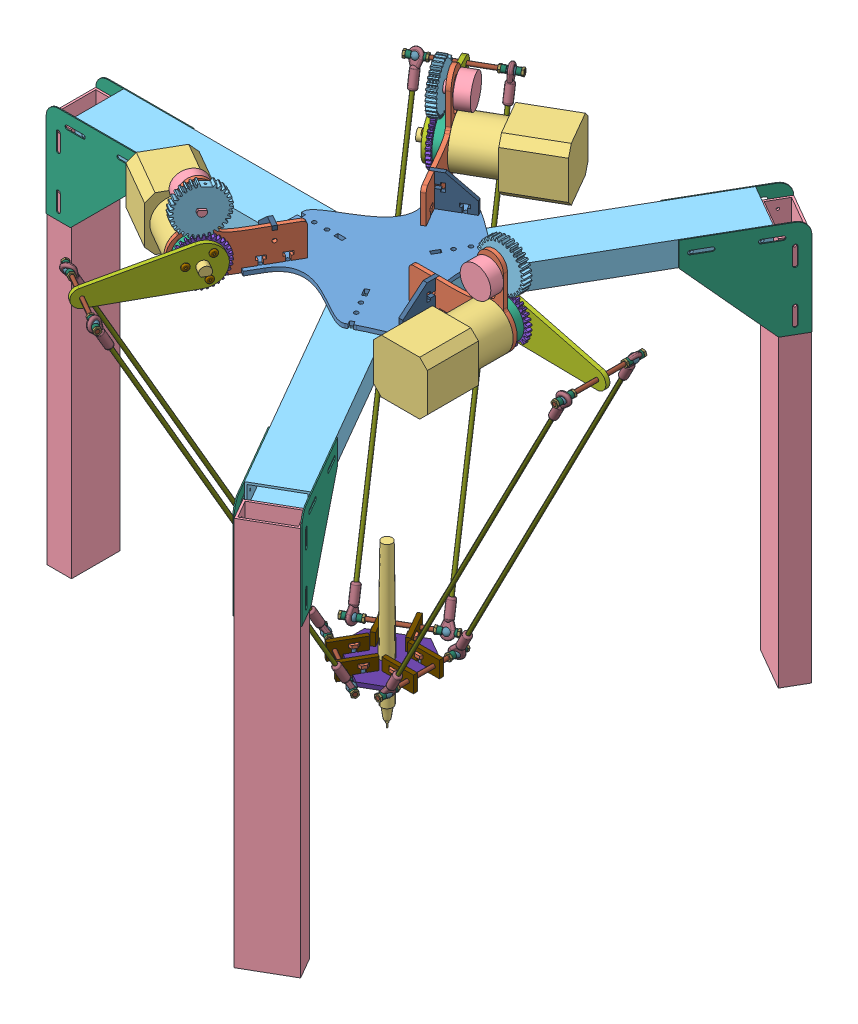
SolidWorks assembly robot, configuration Default. Lengths in mm.
Overall size (423 403.55 480.6).
179 component instances, 24 part files, 17 mates.
Components (placement in the parent):
- robot_base-2: robot_base [Default] at (60.4446 67.0831 10.1003) size (316.06 87.11 312.23)
  - baseplate-1: baseplate [Default] at (-6.2424 -10.4202 4.8167) size (143.92 3.17 142.53)
  - motor_plate-1: motor_plate [Default] at (95.6116 7.5795 20.7552) x (-1 0 0) z (0 0 -1) size (81.5 68.48 3.17)
  - stepper-1: stepper [Default] at (95.6116 7.5795 90.9552) x (0 0 -1) z (-1 0 0) size (92.2 42 42)
  - potentiometer2-1: potentiometer2 [Default] at (95.6111 42.9686 32.2552) x (0 0 -1) z (-0.02281 0.99974 0) size (26.5 24 24)
  - gear_pot-1: gear_pot [Default] at (95.6111 42.9686 6.4052) x (-0.303545 0.952817 0) z (0 0 1) size (37.03 37 6.35)
  - arm_upper_complete-1: arm_upper_complete [Default] at (88.6637 -5.6723 10.8016) x (0.795225 0.606314 0) z (0.606314 -0.795225 0) size (88.08 14.2 88.05) (flexible)
    - arm_collar-1: arm_collar [Default] at (13.5599 -1.2214 -6.3255) size (30.48 6.35 30.25)
    - arm_upper-1: arm_upper [Default] at (13.5599 -7.5714 -6.3255) x (-0.707107 0 -0.707107) z (0 1 0) size (92.08 30.48 3.17)
    - gear_stepper-1: gear_stepper [Default] at (13.5599 -4.3964 -6.3255) x (-0.959493 0 0.281733) z (0 1 0) size (37.03 37 3.17)
    - 4-40_12_screw-1: 4-40_12_screw [Default] at (4.761 5.1286 -1.2455) x (0.825951 0 0.563741) z (0.563741 0 -0.825951) size (5.41 14.2 5.41)
    - 4-40_12_screw-2: 4-40_12_screw [Default] at (22.3587 5.1286 -1.2455) x (0.604288 0 0.796766) z (0.796766 0 -0.604288) size (5.41 14.2 5.41)
    - 4-40_12_screw-3: 4-40_12_screw [Default] at (13.5599 5.1286 -16.4855) x (-0.60826 0 0.793738) z (0.793738 0 0.60826) size (5.41 14.2 5.41)
  - motor_plate_support-1: motor_plate_support [Default] at (49.4471 6.4708 20.7552) x (0 0 -1) z (1 0 0) size (28.57 28.57 3.17)
  - arm_upper_complete-4: arm_upper_complete [Default] at (-48.1298 -6.4819 -82.7041) x (-0.353553 0.707107 -0.612372) z (-0.353553 -0.707107 -0.612372) size (88.08 14.2 88.05) (flexible)
    - arm_collar-1: arm_collar [Default] at (13.5599 -1.2214 -6.3255) size (30.48 6.35 30.25)
    - arm_upper-1: arm_upper [Default] at (13.5599 -7.5714 -6.3255) x (-0.707107 0 -0.707107) z (0 1 0) size (92.08 30.48 3.17)
    - gear_stepper-1: gear_stepper [Default] at (13.5599 -4.3964 -6.3255) x (-0.959493 0 0.281733) z (0 1 0) size (37.03 37 3.17)
    - 4-40_12_screw-1: 4-40_12_screw [Default] at (4.761 5.1286 -1.2455) x (0.952213 0 0.305436) z (0.305436 0 -0.952213) size (5.41 14.2 5.41)
    - 4-40_12_screw-2: 4-40_12_screw [Default] at (22.3587 5.1286 -1.2455) x (0.806013 0 0.591898) z (0.591898 0 -0.806013) size (5.41 14.2 5.41)
    - 4-40_12_screw-3: 4-40_12_screw [Default] at (13.5599 5.1286 -16.4855) x (-0.35728 0 0.933997) z (0.933997 0 0.35728) size (5.41 14.2 5.41)
  - arm_upper_complete-5: arm_upper_complete [Default] at (-60.2082 -5.7041 83.3183) x (-0.396211 0.609973 0.686257) z (-0.304987 -0.792422 0.528252) size (88.08 14.2 88.05) (flexible)
    - arm_collar-1: arm_collar [Default] at (13.5599 -1.2214 -6.3255) size (30.48 6.35 30.25)
    - arm_upper-1: arm_upper [Default] at (13.5599 -7.5714 -6.3255) x (-0.707107 0 -0.707107) z (0 1 0) size (92.08 30.48 3.17)
    - gear_stepper-1: gear_stepper [Default] at (13.5599 -4.3964 -6.3255) x (-0.959493 0 0.281733) z (0 1 0) size (37.03 37 3.17)
    - 4-40_12_screw-1: 4-40_12_screw [Default] at (4.761 5.1286 -1.2455) x (0.645771 0 0.763531) z (0.763531 0 -0.645771) size (5.41 14.2 5.41)
    - 4-40_12_screw-2: 4-40_12_screw [Default] at (22.3587 5.1286 -1.2455) x (0.370008 0 0.929029) z (0.929029 0 -0.370008) size (5.41 14.2 5.41)
    - 4-40_12_screw-3: 4-40_12_screw [Default] at (13.5599 5.1286 -16.4855) x (-0.797851 0 0.602855) z (0.602855 0 0.797851) size (5.41 14.2 5.41)
  - stepper-4: stepper [Default] at (-131.7676 7.5795 49.9556) x (0.866025 0 0.5) z (0.5 0 -0.866025) size (92.2 42 42)
  - stepper-5: stepper [Default] at (17.4285 7.5792 -126.461) x (-0.866025 0 0.5) z (0.5 0 0.866025) size (92.2 42 42)
  - motor_plate-4: motor_plate [Default] at (-70.9726 7.5795 85.0556) x (0.5 0 -0.866025) z (0.866025 0 0.5) size (81.5 68.48 3.17)
  - motor_plate-5: motor_plate [Default] at (-43.3663 7.5795 -91.3607) x (0.5 0 0.866025) z (-0.866025 0 0.5) size (81.5 68.48 3.17)
  - motor_plate_support-4: motor_plate_support [Default] at (-47.8903 6.4708 45.076) x (0.866025 0 0.5) z (-0.5 0 0.866025) size (28.57 28.57 3.17)
  - motor_plate_support-5: motor_plate_support [Default] at (-20.2841 6.4708 -51.3811) x (-0.866025 0 0.5) z (-0.5 0 -0.866025) size (28.57 28.57 3.17)
  - potentiometer2-6: potentiometer2 [Default] at (-80.9316 43.0542 79.3052) x (0.866025 0 0.5) z (-0.489802 0.200934 0.848363) size (26.5 24 24)
  - potentiometer2-7: potentiometer2 [Default] at (-33.4068 43.0538 -97.1103) x (-0.866025 0 0.5) z (-0.387537 -0.631871 -0.671234) size (26.5 24 24)
  - gear_pot-6: gear_pot [Default] at (-48.9952 43.0538 -88.1103) x (0.28283 0.824639 0.489875) z (-0.866025 0 0.5) size (37.03 37 6.35)
  - gear_pot-7: gear_pot [Default] at (-65.3432 43.0542 88.3052) x (0.498267 0.083192 -0.863023) z (0.866025 0 0.5) size (37.03 37 6.35)
- arm_lower-1: arm_lower [Default] at (70.1513 -45.1776 28.3523) x (0.25 0.866025 0.433013) z (0.433013 -0.5 0.75) size (202.96 71.67 273.76) (flexible)
  - elbow-1: elbow [Default] at (-138.5078 -10.2069 -41.2303) x (0.406722 0 -0.913552) z (0.913552 0 0.406722) size (27.91 71.32 18.46) (flexible)
    - elbow_rod-1: elbow_rod [Default] at (-82.9284 -17.3054 -7.7817) size (2.95 69.85 2.95)
    - 4-40_nut-2: 4-40_nut [Default] at (-82.9284 50.9571 -7.7817) x (-0.925515 0 -0.37871) z (0.37871 0 -0.925515) size (5.5 1.59 4.76)
    - balljoint-1: balljoint [Default] at (-70.1601 46.0339 -3.1373) x (0.978228 -0.005688 0.207455) z (0.181962 -0.4572 -0.870551) size (25.24 8.42 10.32) (flexible)
      - balljoint_joint-1: balljoint_joint [Default] at (-6.0674 0.1484 2.2064) size (25.24 5.95 10.32)
      - balljoint_ball-2: balljoint_ball [Default] at (-13.4478 0.1484 2.2064) x (0.504519 0.392199 -0.769182) z (-0.863382 0.235041 -0.446461) size (6.35 5.63 6.35)
    - 4-40_spacer-1: 4-40_spacer [Default] at (-82.9284 47.7821 -7.7817) x (-0.963234 0 -0.268664) z (0.268664 0 -0.963234) size (4.76 3.17 4.76)
    - 4-40_spacer-2: 4-40_spacer [Default] at (-82.9284 38.9821 -7.7817) x (0.50401 0 -0.863698) z (0.863698 0 0.50401) size (4.76 3.17 4.76)
    - 4-40_spacer-4: 4-40_spacer [Default] at (-82.9284 -15.7179 -7.7817) x (0.905892 0 0.423509) z (-0.423509 0 0.905892) size (4.76 3.17 4.76)
    - 4-40_spacer-5: 4-40_spacer [Default] at (-82.9284 -6.9178 -7.7817) x (0.243086 0 0.970005) z (-0.970005 0 0.243086) size (4.76 3.17 4.76)
    - 4-40_nut-4: 4-40_nut [Default] at (-82.9284 -17.3054 -7.7817) x (0.990683 0 0.13619) z (-0.13619 0 0.990683) size (5.5 1.59 4.76)
    - balljoint-2: balljoint [Default] at (-69.5996 -7.7385 -5.7548) x (0.978228 -0.005688 0.207455) z (-0.065537 -0.956939 0.282794) size (25.24 9.66 10.32) (flexible)
      - balljoint_joint-1: balljoint_joint [Default] at (-6.0674 0.1484 2.2064) size (25.24 5.95 10.32)
      - balljoint_ball-2: balljoint_ball [Default] at (-13.4478 0.1484 2.2064) x (0.773112 0.608228 0.179876) z (-0.634244 0.738798 0.227842) size (6.35 5.63 6.35)
    - 4-40_nut-5: 4-40_nut [Default] at (-82.9284 37.3946 -7.7817) x (-0.730308 0 0.683118) z (-0.683118 0 -0.730308) size (5.5 1.59 4.76)
    - 4-40_nut-6: 4-40_nut [Default] at (-82.9284 -3.7428 -7.7817) x (0.364982 0 0.931015) z (-0.931015 0 0.364982) size (5.5 1.59 4.76)
  - arm_lower_rod-1: arm_lower_rod [Default] at (4.1195 32.9863 -221.4086) x (0.772258 -0.295149 0.562587) z (-0.242059 -0.955434 -0.168975) size (2.79 304.8 2.79)
  - arm_lower_rod-2: arm_lower_rod [Default] at (4.1195 -21.7137 -221.4086) x (-0.180394 -0.975737 -0.124075) z (-0.788945 0.21887 -0.574162) size (2.79 304.8 2.79)
  - elbow-2: elbow [Default] at (1.2211 -2.2794 -218.4531) x (-0.919495 0 0.393101) z (-0.393101 0 -0.919495) size (26.99 69.85 21.82) (flexible)
    - elbow_rod-1: elbow_rod [Default] at (-10.2986 -27.0522 5.4483) x (-0.995719 0 0.092427) z (-0.092427 0 -0.995719) size (2.95 69.85 2.95)
    - 4-40_nut-2: 4-40_nut [Default] at (-10.2986 41.2103 5.4483) x (-0.979976 0 -0.199116) z (0.199116 0 -0.979976) size (5.5 1.59 4.76)
    - balljoint-1: balljoint [Default] at (0.9596 33.1631 -1.9507) x (0.858231 0.005688 -0.513232) z (0.161094 0.946425 0.279871) size (25.24 8.21 10.32) (flexible)
      - balljoint_joint-1: balljoint_joint [Default] at (-6.0674 0.1484 2.2064) size (25.24 5.95 10.32)
      - balljoint_ball-2: balljoint_ball [Default] at (-13.4478 0.1484 2.2064) x (-0.187535 -0.929304 0.318159) z (-0.982242 0.179297 -0.055264) size (6.35 5.63 6.35)
    - 4-40_spacer-1: 4-40_spacer [Default] at (-10.2986 38.0353 5.4483) x (-0.636577 0 0.771213) z (-0.771213 0 -0.636577) size (4.76 3.17 4.76)
    - 4-40_spacer-2: 4-40_spacer [Default] at (-10.2986 29.2353 5.4483) x (-0.584045 0 -0.811722) z (0.811722 0 -0.584045) size (4.76 3.17 4.76)
    - 4-40_spacer-4: 4-40_spacer [Default] at (-10.2986 -25.4647 5.4483) x (0.755341 0 -0.655332) z (0.655332 0 0.755341) size (4.76 3.17 4.76)
    - 4-40_spacer-5: 4-40_spacer [Default] at (-10.2986 -16.6646 5.4483) x (0.985019 0 0.172447) z (-0.172447 0 0.985019) size (4.76 3.17 4.76)
    - 4-40_nut-4: 4-40_nut [Default] at (-10.2986 -27.0522 5.4483) x (0.846045 0 -0.533112) z (0.533112 0 0.846045) size (5.5 1.59 4.76)
    - balljoint-2: balljoint [Default] at (0.1112 -19.5526 -3.3474) x (0.858231 0.005688 -0.513232) z (0.513231 0.00161 0.858249) size (25.24 7.19 10.32) (flexible)
      - balljoint_joint-1: balljoint_joint [Default] at (-6.0674 0.1484 2.2064) size (25.24 5.95 10.32)
      - balljoint_ball-2: balljoint_ball [Default] at (-13.4478 0.1484 2.2064) x (0.476593 -0.004126 0.879115) z (-0.879106 0.004233 0.476608) size (6.35 5.63 6.35)
    - 4-40_nut-5: 4-40_nut [Default] at (-10.2986 27.6478 5.4483) x (0.327035 0 0.945012) z (-0.945012 0 0.327035) size (5.5 1.59 4.76)
    - 4-40_nut-6: 4-40_nut [Default] at (-10.2986 -13.4896 5.4483) x (0.998977 0 0.04523) z (-0.04523 0 0.998977) size (5.5 1.59 4.76)
- arm_lower-2: arm_lower [Default] at (80.1493 -169.0961 -44.214) x (0.413591 0.561933 -0.716361) z (0.280966 -0.827183 -0.486648) size (96.01 120.18 326.37) (flexible)
  - elbow-1: elbow [Default] at (-29.8278 -40.9337 -53.8462) size (16.96 71.03 27.91) (flexible)
    - elbow_rod-1: elbow_rod [Default] at (-66.4875 -0.2803 45.3338) size (2.95 69.85 2.95)
    - 4-40_nut-2: 4-40_nut [Default] at (-66.4875 67.9822 45.3338) x (-0.41332 0 0.910586) z (-0.910586 0 -0.41332) size (5.5 1.59 4.76)
    - balljoint-1: balljoint [Default] at (-64.9785 64.7016 32.0624) x (0.105005 0.037146 -0.993778) z (-0.110377 -0.992693 -0.048768) size (25.24 7.48 10.32) (flexible)
      - balljoint_joint-1: balljoint_joint [Default] at (-6.0674 0.1484 2.2064) size (25.24 5.95 10.32)
      - balljoint_ball-2: balljoint_ball [Default] at (-13.4478 0.1484 2.2064) x (-0.15925 0.980003 -0.119303) z (-0.986539 -0.162518 -0.01812) size (6.35 5.63 6.35)
    - 4-40_spacer-1: 4-40_spacer [Default] at (-66.4875 64.8072 45.3338) x (-0.304773 0 0.952425) z (-0.952425 0 -0.304773) size (4.76 3.17 4.76)
    - 4-40_spacer-2: 4-40_spacer [Default] at (-66.4875 56.0072 45.3338) x (-0.84409 0 -0.536201) z (0.536201 0 -0.84409) size (4.76 3.17 4.76)
    - 4-40_spacer-4: 4-40_spacer [Default] at (-66.4875 1.3072 45.3338) x (0.457347 0 -0.889288) z (0.889288 0 0.457347) size (4.76 3.17 4.76)
    - 4-40_spacer-5: 4-40_spacer [Default] at (-66.4875 10.1073 45.3338) x (0.978477 0 -0.206358) z (0.206358 0 0.978477) size (4.76 3.17 4.76)
    - 4-40_nut-4: 4-40_nut [Default] at (-66.4875 -0.2803 45.3338) x (0.587007 0 -0.809582) z (0.809582 0 0.587007) size (5.5 1.59 4.76)
    - balljoint-2: balljoint [Default] at (-65.5235 5.6326 31.8415) x (0.105005 0.037146 -0.993778) z (0.267511 0.961413 0.064203) size (25.24 9.14 10.32) (flexible)
      - balljoint_joint-1: balljoint_joint [Default] at (-6.0674 0.1484 2.2064) size (25.24 5.95 10.32)
      - balljoint_ball-2: balljoint_ball [Default] at (-13.4478 0.1484 2.2064) x (0.193512 -0.945829 0.260693) z (-0.980394 -0.176361 0.087883) size (6.35 5.63 6.35)
    - 4-40_nut-5: 4-40_nut [Default] at (-66.4875 54.4197 45.3338) x (0.65511 0 0.755533) z (-0.755533 0 0.65511) size (5.5 1.59 4.76)
    - 4-40_nut-6: 4-40_nut [Default] at (-66.4875 13.2823 45.3338) x (0.944108 0 -0.329637) z (0.329637 0 0.944108) size (5.5 1.59 4.76)
  - arm_lower_rod-1: arm_lower_rod [Default] at (-63.5179 32.6633 -318.9096) x (0.821322 0.560202 0.107723) z (0.560717 -0.827523 0.028315) size (2.79 304.8 2.79)
  - arm_lower_rod-2: arm_lower_rod [Default] at (-63.5179 -22.0367 -318.9096) x (0.623751 -0.78076 0.036723) z (-0.774537 -0.623726 -0.105154) size (2.79 304.8 2.79)
  - elbow-2: elbow [Default] at (-74.9143 -2.2794 -279.9861) x (-0.798144 0 0.602467) z (-0.602467 0 -0.798144) size (27.87 71.97 26.84) (flexible)
    - elbow_rod-1: elbow_rod [Default] at (-37.6927 -27.0522 29.7046) x (-0.701235 0 0.71293) z (-0.71293 0 -0.701235) size (2.95 69.85 2.95)
    - 4-40_nut-2: 4-40_nut [Default] at (-37.6927 41.2103 29.7046) x (-0.903452 0 -0.42869) z (0.42869 0 -0.903452) size (5.5 1.59 4.76)
    - balljoint-1: balljoint [Default] at (-29.8663 33.4489 18.6895) x (0.682527 -0.037146 -0.729916) z (0.636868 0.520176 0.569048) size (25.24 9.25 10.56) (flexible)
      - balljoint_joint-1: balljoint_joint [Default] at (-6.0674 0.1484 2.2064) size (25.24 5.95 10.32)
      - balljoint_ball-2: balljoint_ball [Default] at (-13.4478 0.1484 2.2064) x (-0.652309 -0.415043 0.634217) z (-0.757042 0.315757 -0.572001) size (6.35 5.63 6.35)
    - 4-40_spacer-1: 4-40_spacer [Default] at (-37.6927 38.0353 29.7046) x (-0.803194 0 0.595717) z (-0.595717 0 -0.803194) size (4.76 3.17 4.76)
    - 4-40_spacer-2: 4-40_spacer [Default] at (-37.6927 29.2353 29.7046) x (-0.371956 0 -0.92825) z (0.92825 0 -0.371956) size (4.76 3.17 4.76)
    - 4-40_spacer-4: 4-40_spacer [Default] at (-37.6927 -25.4647 29.7046) x (0.890645 0 -0.4547) z (0.4547 0 0.890645) size (4.76 3.17 4.76)
    - 4-40_spacer-5: 4-40_spacer [Default] at (-37.6927 -16.6646 29.7046) x (0.914753 0 0.404013) z (-0.404013 0 0.914753) size (4.76 3.17 4.76)
    - 4-40_nut-4: 4-40_nut [Default] at (-37.6927 -27.0522 29.7046) x (0.949333 0 -0.314271) z (0.314271 0 0.949333) size (5.5 1.59 4.76)
    - balljoint-2: balljoint [Default] at (-29.7906 -18.6823 18.6296) x (0.682527 -0.037146 -0.729916) z (0.545757 -0.63836 0.542812) size (25.24 8.74 10.32) (flexible)
      - balljoint_joint-1: balljoint_joint [Default] at (-6.0674 0.1484 2.2064) size (25.24 5.95 10.32)
      - balljoint_ball-2: balljoint_ball [Default] at (-13.4478 0.1484 2.2064) x (-0.025763 0.637852 0.769728) z (-0.998978 -0.045039 0.003886) size (6.35 5.63 6.35)
    - 4-40_nut-5: 4-40_nut [Default] at (-37.6927 27.6478 29.7046) x (0.090454 0 0.995901) z (-0.995901 0 0.090454) size (5.5 1.59 4.76)
    - 4-40_nut-6: 4-40_nut [Default] at (-37.6927 -13.4896 29.7046) x (0.958862 0 0.283874) z (-0.283874 0 0.958862) size (5.5 1.59 4.76)
- arm_lower-3: arm_lower [Default] at (166.041 -220.5584 22.0117) x (-0.999733 0.023126 0) z (-0.023126 -0.999733 0) size (140.16 90.66 307.5) (flexible)
  - elbow-1: elbow [Default] at (-17.6687 -3.4919 11.6959) size (20.85 69.85 27.83) (flexible)
    - elbow_rod-1: elbow_rod [Default] at (109.8643 -11.4103 -13.9452) x (-0.568788 0 -0.822484) z (0.822484 0 -0.568788) size (2.95 69.85 2.95)
    - 4-40_nut-2: 4-40_nut [Default] at (109.8643 56.8522 -13.9452) x (0.719644 0 -0.694343) z (0.694343 0 0.719644) size (5.5 1.59 4.76)
    - balljoint-1: balljoint [Default] at (101.9784 51.2691 -25.053) x (-0.452691 -0.040419 -0.890751) z (0.786743 -0.488258 -0.377677) size (25.24 8.5 10.32) (flexible)
      - balljoint_joint-1: balljoint_joint [Default] at (-6.0674 0.1484 2.2064) size (25.24 5.95 10.32)
      - balljoint_ball-2: balljoint_ball [Default] at (-13.4478 0.1484 2.2064) x (0.896164 -0.184474 -0.403558) z (0.441877 0.453871 0.773787) size (6.35 5.63 6.35)
    - 4-40_spacer-1: 4-40_spacer [Default] at (109.8643 53.6772 -13.9452) x (0.634138 0 -0.77322) z (0.77322 0 0.634138) size (4.76 3.17 4.76)
    - 4-40_spacer-2: 4-40_spacer [Default] at (109.8643 44.8772 -13.9452) x (0.587264 0 0.809396) z (-0.809396 0 0.587264) size (4.76 3.17 4.76)
    - 4-40_spacer-4: 4-40_spacer [Default] at (109.8643 -9.8228 -13.9452) x (-0.752732 0 0.658327) z (-0.658327 0 -0.752732) size (4.76 3.17 4.76)
    - 4-40_spacer-5: 4-40_spacer [Default] at (109.8643 -1.0227 -13.9452) x (-0.985696 0 -0.168533) z (0.168533 0 -0.985696) size (4.76 3.17 4.76)
    - 4-40_nut-4: 4-40_nut [Default] at (109.8643 -11.4103 -13.9452) x (0.864411 0 0.502787) z (-0.502787 0 0.864411) size (5.5 1.59 4.76)
    - balljoint-2: balljoint [Default] at (102.9847 -2.3374 -25.614) x (-0.452691 -0.040419 -0.890751) z (0.30248 -0.946698 -0.110766) size (25.24 10.34 10.32) (flexible)
      - balljoint_joint-1: balljoint_joint [Default] at (-6.0674 0.1484 2.2064) size (25.24 5.95 10.32)
      - balljoint_ball-2: balljoint_ball [Default] at (-13.4478 0.1484 2.2064) x (0.686752 -0.679322 -0.258639) z (0.725767 0.6606 0.192012) size (6.35 5.63 6.35)
    - 4-40_nut-5: 4-40_nut [Default] at (109.8643 43.2897 -13.9452) x (-0.330786 0 -0.943706) z (0.943706 0 -0.330786) size (5.5 1.59 4.76)
    - 4-40_nut-6: 4-40_nut [Default] at (109.8643 2.1523 -13.9452) x (-0.999148 0 -0.041262) z (0.041262 0 -0.999148) size (5.5 1.59 4.76)
  - arm_lower_rod-1: arm_lower_rod [Default] at (-49.1981 34.7482 -280.4671) x (0.720121 -0.605681 -0.338491) z (-0.525829 -0.79468 0.303293) size (2.79 304.8 2.79)
  - arm_lower_rod-2: arm_lower_rod [Default] at (-49.1981 -19.9518 -280.4671) x (-0.467392 -0.839977 0.27565) z (-0.759352 0.541114 0.361358) size (2.79 304.8 2.79)
  - elbow-2: elbow [Default] at (1.2211 -2.2794 -218.4531) x (-0.919495 0 0.393101) z (-0.393101 0 -0.919495) size (13.91 69.9 27.15) (flexible)
    - elbow_rod-1: elbow_rod [Default] at (22.4808 -25.5522 84.3594) x (0.273322 0 0.961923) z (-0.961923 0 0.273322) size (2.95 69.85 2.95)
    - 4-40_nut-2: 4-40_nut [Default] at (22.4808 42.7103 84.3594) x (-0.979976 0 -0.199116) z (0.199116 0 -0.979976) size (5.5 1.59 4.76)
    - balljoint-1: balljoint [Default] at (21.5122 35.058 70.8678) x (-0.066092 0.040419 -0.996995) z (0.102925 0.994125 0.03348) size (25.24 7.8 10.32) (flexible)
      - balljoint_joint-1: balljoint_joint [Default] at (-6.0674 0.1484 2.2064) size (25.24 5.95 10.32)
      - balljoint_ball-2: balljoint_ball [Default] at (-13.4478 0.1484 2.2064) x (-0.959128 -0.274983 0.066769) z (-0.280071 0.956192 -0.085185) size (6.35 5.63 6.35)
    - 4-40_spacer-1: 4-40_spacer [Default] at (22.4808 39.5353 84.3594) x (-0.636577 0 0.771213) z (-0.771213 0 -0.636577) size (4.76 3.17 4.76)
    - 4-40_spacer-2: 4-40_spacer [Default] at (22.4808 30.7353 84.3594) x (-0.584045 0 -0.811722) z (0.811722 0 -0.584045) size (4.76 3.17 4.76)
    - 4-40_spacer-4: 4-40_spacer [Default] at (22.4808 -23.9647 84.3594) x (0.755341 0 -0.655332) z (0.655332 0 0.755341) size (4.76 3.17 4.76)
    - 4-40_spacer-5: 4-40_spacer [Default] at (22.4808 -15.1646 84.3594) x (0.985019 0 0.172447) z (-0.172447 0 0.985019) size (4.76 3.17 4.76)
    - 4-40_nut-4: 4-40_nut [Default] at (22.4808 -25.5522 84.3594) x (0.846045 0 -0.533112) z (0.533112 0 0.846045) size (5.5 1.59 4.76)
    - balljoint-2: balljoint [Default] at (19.4802 -18.08 71.0658) x (-0.066092 0.040419 -0.996995) z (0.972206 0.227522 -0.055225) size (25.24 7.1 10.32) (flexible)
      - balljoint_joint-1: balljoint_joint [Default] at (-6.0674 0.1484 2.2064) size (25.24 5.95 10.32)
      - balljoint_ball-2: balljoint_ball [Default] at (-13.4478 0.1484 2.2064) x (-0.565213 -0.165511 0.808171) z (-0.823954 0.161264 -0.543225) size (6.35 5.63 6.35)
    - 4-40_nut-5: 4-40_nut [Default] at (22.4808 29.1478 84.3594) x (0.327035 0 0.945012) z (-0.945012 0 0.327035) size (5.5 1.59 4.76)
    - 4-40_nut-6: 4-40_nut [Default] at (22.4808 -11.9896 84.3594) x (0.998977 0 0.04523) z (-0.04523 0 0.998977) size (5.5 1.59 4.76)
- hand-1: hand [Default] at (44.3121 -218.4887 0.1525) size (60.32 14.2 67.85)
  - hand_base-1: hand_base [Default] at (1.9794 -4.0388 1.6994) size (50.8 3.17 58.66)
  - wrist_connector-2: wrist_connector [Default] at (29.61 2.3112 11.8594) x (0 0 -1) z (1 0 0) size (3.17 12.7 24.77)
  - wrist_connector-6: wrist_connector [Default] at (-20.6348 2.3112 20.5483) x (0.866025 0 0.5) z (-0.5 0 0.866025) size (3.17 12.7 24.77)
  - wrist_connector-7: wrist_connector [Default] at (-3.0372 2.3112 -27.3094) x (-0.866025 0 0.5) z (-0.5 0 -0.866025) size (3.17 12.7 24.77)
  - 4-40_38_screw-3: 4-40_38_screw [Default] at (18.4975 5.4862 11.8594) x (-0.241512 0 0.970398) z (0.970398 0 0.241512) size (5.41 11.02 5.41)
  - 4-40_nut_wide-1: 4-40_nut_wide [Default] at (18.4975 2.8192 11.8594) size (7.33 2.38 6.35)
  - 4-40_nut_wide-4: 4-40_nut_wide [Default] at (-15.0785 2.8192 10.9246) x (-0.5 0 0.866025) z (-0.866025 0 -0.5) size (7.33 2.38 6.35)
  - 4-40_nut_wide-5: 4-40_nut_wide [Default] at (2.5191 2.8192 -17.6857) x (-0.5 0 -0.866025) z (0.866025 0 -0.5) size (7.33 2.38 6.35)
  - 4-40_38_screw-4: 4-40_38_screw [Default] at (-15.0785 5.4862 10.9246) x (-0.719633 0 -0.694354) z (-0.694354 0 0.719633) size (5.41 11.02 5.41)
  - 4-40_38_screw-5: 4-40_38_screw [Default] at (2.5191 5.4862 -17.6857) x (0.961145 0 -0.276044) z (-0.276044 0 -0.961145) size (5.41 11.02 5.41)
  - 4-40_38_screw-8: 4-40_38_screw [Default] at (18.4975 5.4862 -8.4606) x (-0.241512 0 0.970398) z (0.970398 0 0.241512) size (5.41 11.02 5.41)
  - 4-40_nut_wide-8: 4-40_nut_wide [Default] at (18.4975 2.8192 -8.4606) size (7.33 2.38 6.35)
  - wrist_connector-11: wrist_connector [Default] at (29.61 2.3112 -8.4606) x (0 0 -1) z (1 0 0) size (3.17 12.7 24.77)
  - wrist_connector-12: wrist_connector [Default] at (-3.0372 2.3112 30.7083) x (0.866025 0 0.5) z (-0.5 0 0.866025) size (3.17 12.7 24.77)
  - wrist_connector-13: wrist_connector [Default] at (-20.6348 2.3112 -17.1494) x (-0.866025 0 0.5) z (-0.5 0 -0.866025) size (3.17 12.7 24.77)
  - 4-40_nut_wide-9: 4-40_nut_wide [Default] at (2.5191 2.8192 21.0846) x (-0.5 0 0.866025) z (-0.866025 0 -0.5) size (7.33 2.38 6.35)
  - 4-40_nut_wide-10: 4-40_nut_wide [Default] at (-15.0785 2.8192 -7.5257) x (-0.5 0 -0.866025) z (0.866025 0 -0.5) size (7.33 2.38 6.35)
  - 4-40_38_screw-9: 4-40_38_screw [Default] at (2.5191 5.4862 21.0846) x (-0.719633 0 -0.694354) z (-0.694354 0 0.719633) size (5.41 11.02 5.41)
  - 4-40_38_screw-10: 4-40_38_screw [Default] at (-15.0785 5.4862 -7.5257) x (0.961145 0 -0.276044) z (-0.276044 0 -0.961145) size (5.41 11.02 5.41)
- pen-1: pen [Default] at (46.2915 -219.3525 1.8519) size (9.98 127.05 9.98)
- new_support-1: new_support [Default] at (134.7597 -154.8313 156.4967) x (0.866025 0 -0.5) z (0.5 0 0.866025) size (39.62 314.69 225.09)
  - new_support_lower-1: new_support_lower [Default] at (1.025 -103.1936 69.5673) size (38.1 304.8 19.05)
  - new_support_upper-1: new_support_upper [Default] at (1.025 201.9691 -145.9994) size (38.1 19.05 203.2)
  - gusset_plate-1: gusset_plate [Default] at (-18.787 211.4941 79.0923) x (0 0 -1) z (1 0 0) size (76.2 76.2 0.76)
  - gusset_plate-2: gusset_plate [Default] at (20.075 211.4941 79.0923) x (0 0 -1) z (1 0 0) size (76.2 76.2 0.76)
- new_support-2: new_support [Default] at (136.5351 -154.8313 -125.6377) x (-0.866025 0 -0.5) z (0.5 0 -0.866025) size (39.62 314.69 225.09)
  - new_support_lower-1: new_support_lower [Default] at (1.025 -103.1936 69.5673) size (38.1 304.8 19.05)
  - new_support_upper-1: new_support_upper [Default] at (1.025 201.9691 -145.9994) size (38.1 19.05 203.2)
  - gusset_plate-1: gusset_plate [Default] at (-18.787 211.4941 79.0923) x (0 0 -1) z (1 0 0) size (76.2 76.2 0.76)
  - gusset_plate-2: gusset_plate [Default] at (20.075 211.4941 79.0923) x (0 0 -1) z (1 0 0) size (76.2 76.2 0.76)
- new_support-3: new_support [Default] at (-108.6882 -154.8313 13.892) x (0 0 1) z (-1 0 0) size (39.62 314.69 225.09)
  - new_support_lower-1: new_support_lower [Default] at (1.025 -103.1936 69.5673) size (38.1 304.8 19.05)
  - new_support_upper-1: new_support_upper [Default] at (1.025 201.9691 -145.9994) size (38.1 19.05 203.2)
  - gusset_plate-1: gusset_plate [Default] at (-18.787 211.4941 79.0923) x (0 0 -1) z (1 0 0) size (76.2 76.2 0.76)
  - gusset_plate-2: gusset_plate [Default] at (20.075 211.4941 79.0923) x (0 0 -1) z (1 0 0) size (76.2 76.2 0.76)
Mates (geometry in assembly coordinates):
- Distance1: distance = 18.1877 mm: plane of arm_lower-3/elbow-2/4-40_nut-6 through (225.6685 62.6099 34.6932) normal (0 0 -1); plane of robot_base-2/arm_upper_complete-1/arm_upper-1 through (225.2802 65.3319 16.5055) normal (0 0 1)
- Concentric2: concentric: cylinder of robot_base-2/arm_upper_complete-5/arm_upper-1 through (-34.0327 65.6512 161.5673) axis (0.866025 0 0.5) radius 1.4224; cylinder of arm_lower-2/elbow-2/elbow_rod-1 through (-2.4121 65.6512 179.8234) axis (-0.866025 0 -0.5) radius 1.4732
- Distance2: distance = 18.1877 mm: plane of arm_lower-2/elbow-2/4-40_nut-6 through (-49.2082 63.154 151.4767) normal (0.866025 0 0.5); plane of robot_base-2/arm_upper_complete-5/arm_upper-1 through (-34.0327 65.6512 161.5673) normal (-0.866025 0 -0.5)
- Distance3: distance = 18.1877 mm: plane of arm_lower-1/elbow-2/4-40_nut-6 through (-12.8835 74.2345 -143.8311) normal (-0.866025 0 0.5); plane of robot_base-2/arm_upper_complete-4/arm_upper-1 through (-28.9753 74.6622 -135.3276) normal (0.866025 0 -0.5)
- Concentric4: concentric: cylinder of arm_lower-1/elbow-1/elbow_rod-1 through (2.2304 -216.1775 -4.6145) axis (0.866025 0 -0.5) radius 1.4732; cylinder of hand-1/wrist_connector-7 through (42.6498 -216.1775 -27.9507) axis (-0.866025 0 0.5) radius 1.5875
- Distance4: distance = 8.0277 mm: plane of hand-1/wrist_connector-7 through (40.2685 -209.8275 -32.0751) normal (0.866025 0 -0.5); plane of arm_lower-1/elbow-1/4-40_nut-6 through (48.9691 -213.7365 -33.0606) normal (-0.866025 0 0.5)
- Concentric6: concentric: cylinder of arm_lower-2/elbow-1/elbow_rod-1 through (62.7219 -216.1775 43.2431) axis (-0.866025 0 -0.5) radius 1.4732; cylinder of hand-1/wrist_connector-6 through (22.3025 -216.1775 19.907) axis (0.866025 0 0.5) radius 1.5875
- Distance5: distance = 8.0277 mm: plane of arm_lower-2/elbow-1/4-40_nut-6 through (14.8036 -213.6547 16.8403) normal (0.866025 0 0.5); plane of hand-1/wrist_connector-6 through (19.9213 -209.8275 24.0315) normal (-0.866025 0 -0.5)
- Distance6: distance = 7.8905 mm: plane of hand-1/wrist_connector-11 through (78.6846 -209.8275 -9.8956) normal (0 0 -1); plane of arm_lower-3/elbow-1/4-40_nut-5 through (76.6352 -215.7304 -17.7861) normal (0 0 1)
- Concentric7: concentric: cylinder of arm_lower-3/elbow-1/elbow_rod-1 through (73.9221 -216.1775 -32.9361) axis (0 0 1) radius 1.4732; cylinder of hand-1/wrist_connector-11 through (73.9221 -216.1775 -6.7206) axis (0 0 -1) radius 1.5875
- Concentric8: concentric anti-aligned: cylinder of hand-1/hand_base-1 through (46.2915 -219.3525 1.8519) axis (0 -1 0) radius 4.3656; cylinder of pen-1 through (46.2915 -251.547 1.8519) axis (0 1 0) radius 4.5466
- Coincident18: coincident anti-aligned: plane of hand-1/hand_base-1 through (69.1596 -219.3525 -17.1981) normal (0 1 0); plane of pen-1 through (46.2915 -219.3525 1.8519) normal (0 -1 0)
- Coincident21: coincident anti-aligned: plane of robot_base-2/baseplate-1 through (93.3331 56.6628 -4.5836) normal (0 -1 0); plane of new_support-1/new_support_upper-1 through (147.7499 56.6628 215.0464) normal (0 1 0)
- Parallel1: parallel anti-aligned: plane of robot_base-2/baseplate-1 through (69.8645 59.8378 38.8699) normal (-0.866025 0 0.5); plane of new_support-1/new_support_upper-1 through (180.7455 56.6628 195.9964) normal (0.866025 0 -0.5)
- Tangent1: tangent anti-aligned: plane of robot_base-2/baseplate-1 through (67.1149 59.8378 40.4574) normal (0.5 0 0.866025); cylinder of new_support-1/new_support_upper-1 through (68.9977 37.6118 40.5436) axis (0 1 0) radius 1.016
- Distance7: distance = 17.4625 mm: line of new_support-1/new_support_upper-1 through (180.7455 56.6628 195.9964) axis (-0.5 0 -0.866025); line of robot_base-2/baseplate-1 through (73.0395 56.6628 44.3692) axis (-0.5 0 -0.866025)
- Concentric9: concentric: cylinder of robot_base-2/arm_upper_complete-1/arm_upper-1 through (225.2802 65.3319 16.5055) axis (0 0 -1) radius 1.4224; cylinder of arm_lower-3/elbow-2/elbow_rod-1 through (225.2802 65.3319 -20.0068) axis (0 0 1) radius 1.4732
